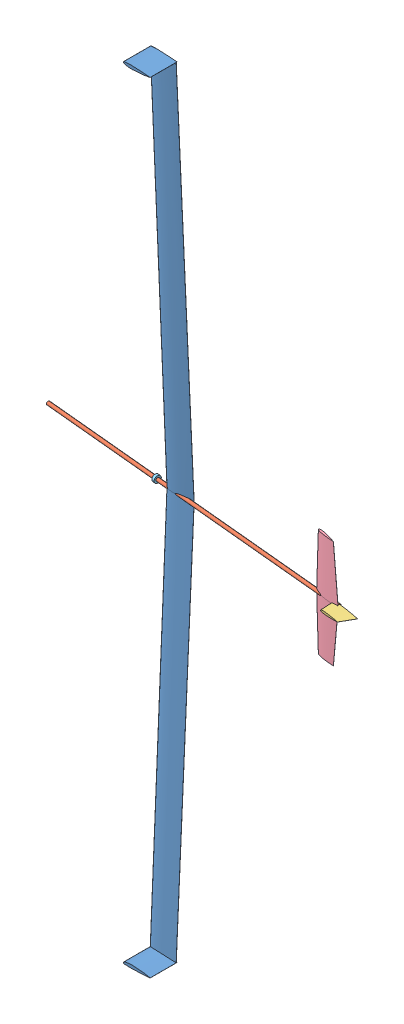
SolidWorks assembly GliderReal, configuration Default. Lengths in mm.
Overall size (1935.72 4441.07 336.2).
5 component instances, 5 part files, 9 mates.
Components (placement in the parent):
- MainWing-1: MainWing [Default] at (1566.5715 2255.6042 3187.5373) size (243.89 4441.07 260.74)
- dowel-1: dowel [Default] at (818.6248 2255.6042 3113.2645) x (0.995566 0 0.09407) z (-0.051797 -0.834754 0.548182) size (1828.8 19.05 19.05)
- Vertical Stabilizer-1: Vertical Stabilizer [Default] at (2601.3841 2255.6042 3281.7158) x (0.995566 0 0.09407) z (0 1 0) size (201.52 106.68 18.3)
- horizontal Stabilizer-1: horizontal Stabilizer [Default] at (2494.9108 2255.6042 3267.7745) x (0.980895 0 0.194539) z (-0.194539 0 0.980895) size (207.45 609.61 18.66)
- ballast-1: ballast [Default] at (1496.0747 2255.6042 3177.2761) x (0.076326 0.584522 -0.80778) z (0.995566 0 0.09407) size (37.34 37.34 14.9)
Mates (geometry in assembly coordinates):
- Concentric3: concentric: cylinder of dowel-1 through (2639.3151 2255.6042 3285.2998) axis (-0.995566 0 -0.09407) radius 9.525; line of Vertical Stabilizer-1 through (2639.3151 2255.6042 3285.2998) axis (-0.995566 0 -0.09407)
- Perpendicular1: perpendicular: line of MainWing-1 through (1604.6715 2255.6042 3199.2213) axis (0 0 -1); line of Vertical Stabilizer-1 through (2639.3151 2264.6587 3285.2998) axis (0 -1 0)
- Coincident9: coincident: plane of dowel-1 through (2639.3151 2255.6042 3285.2998) normal (0.995566 0 0.09407); line of Vertical Stabilizer-1 through (2639.3151 2264.6587 3285.2998) axis (0 -1 0)
- Distance1: distance = 1034.6436 mm: line of Vertical Stabilizer-1 through (2639.3151 2264.6587 3285.2998) axis (0 -1 0); line of MainWing-1 through (1604.6715 2255.6042 3199.2213) axis (0 0 -1)
- Concentric4: concentric: cylinder of dowel-1 through (2639.3151 2255.6042 3285.2998) axis (-0.995566 0 -0.09407) radius 9.525; line of horizontal Stabilizer-1 through (2532.2829 2255.6042 3275.1865) axis (-0.995566 0 -0.09407)
- Perpendicular2: perpendicular: line of Vertical Stabilizer-1 through (2639.3151 2264.6587 3285.2998) axis (0 -1 0); line of horizontal Stabilizer-1 through (2530.5215 2255.6042 3284.0679) axis (0.194539 0 -0.980895)
- Distance4: distance = 931.7431 mm: point of horizontal Stabilizer-1; point of MainWing-1
- Concentric6: concentric: line of MainWing-1 through (1604.6715 2255.6042 3187.5373) axis (-0.995566 0 -0.09407); cylinder of dowel-1 through (2639.3151 2255.6042 3285.2998) axis (-0.995566 0 -0.09407) radius 9.525
- Concentric7: concentric: cylinder of dowel-1 through (2639.3151 2255.6042 3285.2998) axis (-0.995566 0 -0.09407) radius 9.525; cylinder of ballast-1 through (1503.4925 2255.6042 3177.977) axis (-0.995566 0 -0.09407) radius 18.669
